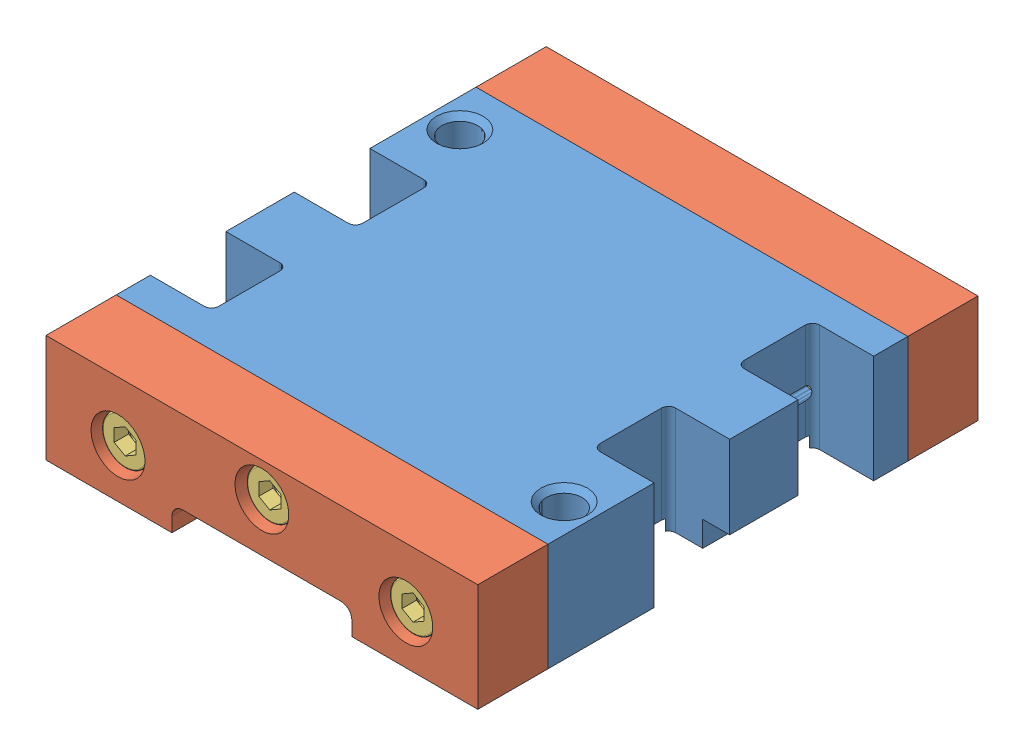
SolidWorks assembly Сборка3, configuration По умолчанию. Lengths in mm.
Overall size (120 30 139).
9 component instances, 3 part files, 16 mates.
Components (placement in the parent):
- Пуансон-2: Пуансон [Default] at (84.7865 149.5092 243.5787) size (120 30 100)
- Боковина пуансона-3: Боковина пуансона [Default] at (84.7865 164.5092 193.5787) x (1 0 0) z (0 0 -1) size (120 30 19.5)
- Боковина пуансона-4: Боковина пуансона [Default] at (84.7865 164.5092 293.5787) x (-1 0 0) z (0 0 1) size (120 30 19.5)
- socket head cap screw_iso-1: socket head cap screw_iso [ISO 4762 M8 x 16 - 16N] at (44.7865 163.0092 311.0787) x (0 0 -1) z (1 0 0) size (24 13 13)
- socket head cap screw_iso-2: socket head cap screw_iso [ISO 4762 M8 x 16 - 16N] at (124.7865 163.0092 311.0787) x (0 0 -1) z (1 0 0) size (24 13 13)
- socket head cap screw_iso-3: socket head cap screw_iso [ISO 4762 M8 x 16 - 16N] at (85.1489 170.29 311.2498) x (0 0 -1) z (1 0 0) size (24 13 13)
- socket head cap screw_iso-4: socket head cap screw_iso [ISO 4762 M8 x 16 - 16N] at (124.7865 163.0092 176.0787) x (0 0 1) z (-1 0 0) size (24 13 13)
- socket head cap screw_iso-5: socket head cap screw_iso [ISO 4762 M8 x 16 - 16N] at (84.7865 170.0092 176.0787) x (0 0 1) z (-1 0 0) size (24 13 13)
- socket head cap screw_iso-6: socket head cap screw_iso [ISO 4762 M8 x 16 - 16N] at (44.7865 163.0092 176.0787) x (0 0 1) z (-1 0 0) size (24 13 13)
Mates (geometry in assembly coordinates):
- Совпадение1: coincident anti-aligned: plane of Пуансон-2 through (144.7865 179.5092 293.5787) normal (0 0 1); plane of Боковина пуансона-4 through (84.7865 164.5092 293.5787) normal (0 0 -1)
- Совпадение2: coincident anti-aligned: plane of Пуансон-2 through (144.7865 179.5092 193.5787) normal (0 0 -1); plane of Боковина пуансона-3 through (84.7865 164.5092 193.5787) normal (0 0 1)
- Концентричный1: concentric anti-aligned: cylinder of Пуансон-2 through (44.7865 163.0092 193.5787) axis (0 0 -1) radius 3.5; cylinder of Боковина пуансона-3 through (44.7865 163.0092 174.0787) axis (0 0 1) radius 4.5
- Концентричный2: concentric anti-aligned: cylinder of Пуансон-2 through (124.7865 163.0092 193.5787) axis (0 0 -1) radius 3.5; cylinder of Боковина пуансона-3 through (124.7865 163.0092 174.0787) axis (0 0 1) radius 4.5
- Концентричный3: concentric anti-aligned: cylinder of Пуансон-2 through (44.7865 163.0092 293.5787) axis (0 0 1) radius 3.5; cylinder of Боковина пуансона-4 through (44.7865 163.0092 313.0787) axis (0 0 -1) radius 4.5
- Концентричный4: concentric anti-aligned: cylinder of Пуансон-2 through (124.7865 163.0092 293.5787) axis (0 0 1) radius 3.5; cylinder of Боковина пуансона-4 through (124.7865 163.0092 313.0787) axis (0 0 -1) radius 4.5
- Концентричный5: concentric aligned: cylinder of Боковина пуансона-4 through (44.7865 163.0092 303.0787) axis (0 0 1) radius 7.5; cylinder of socket head cap screw_iso-1 through (44.7865 163.0092 342.8287) axis (0 0 1) radius 6.5
- Совпадение3: coincident anti-aligned: plane of Боковина пуансона-4 through (44.7865 163.0092 303.0787) normal (0 0 1); plane of socket head cap screw_iso-1 through (44.7865 169.5092 303.0787) normal (0 0 -1)
- Концентричный6: concentric anti-aligned: cylinder of Боковина пуансона-4 through (124.7865 163.0092 313.0787) axis (0 0 -1) radius 4.5; cylinder of socket head cap screw_iso-2 through (124.7865 163.0092 342.8287) axis (0 0 1) radius 6.5
- Совпадение4: coincident anti-aligned: plane of Боковина пуансона-4 through (124.7865 163.0092 303.0787) normal (0 0 1); plane of socket head cap screw_iso-2 through (124.7865 169.5092 303.0787) normal (0 0 -1)
- Концентричный7: concentric anti-aligned: cylinder of Боковина пуансона-3 through (124.7865 163.0092 174.0787) axis (0 0 1) radius 4.5; cylinder of socket head cap screw_iso-4 through (124.7865 163.0092 144.3287) axis (0 0 -1) radius 6.5
- Совпадение5: coincident anti-aligned: plane of Боковина пуансона-3 through (124.7865 163.0092 184.0787) normal (0 0 -1); plane of socket head cap screw_iso-4 through (124.7865 169.5092 184.0787) normal (0 0 1)
- Концентричный8: concentric anti-aligned: cylinder of Боковина пуансона-3 through (84.7865 170.0092 174.0787) axis (0 0 1) radius 4.5; cylinder of socket head cap screw_iso-5 through (84.7865 170.0092 144.3287) axis (0 0 -1) radius 6.5
- Совпадение6: coincident anti-aligned: plane of Боковина пуансона-3 through (84.7865 170.0092 184.0787) normal (0 0 -1); plane of socket head cap screw_iso-5 through (84.7865 176.5092 184.0787) normal (0 0 1)
- Концентричный9: concentric aligned: cylinder of Боковина пуансона-3 through (44.7865 163.0092 184.0787) axis (0 0 -1) radius 7.5; cylinder of socket head cap screw_iso-6 through (44.7865 163.0092 144.3287) axis (0 0 -1) radius 6.5
- Совпадение7: coincident anti-aligned: plane of Боковина пуансона-3 through (44.7865 163.0092 184.0787) normal (0 0 -1); plane of socket head cap screw_iso-6 through (44.7865 169.5092 184.0787) normal (0 0 1)
